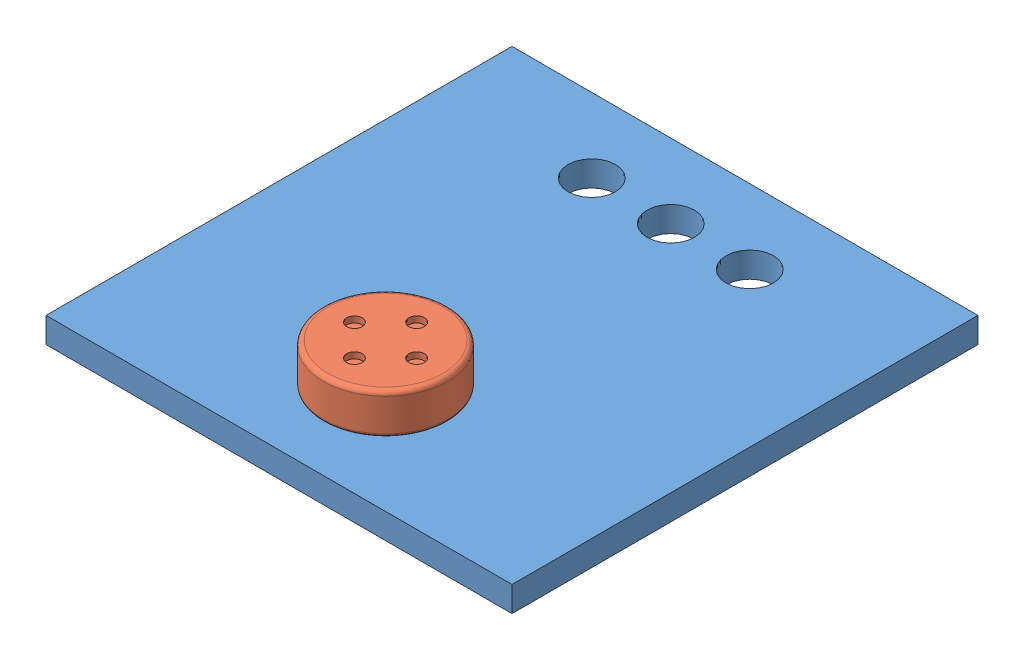
SolidWorks assembly Mic4013onBoard, configuration Default. Lengths in mm.
Overall size (14.99 2.16 14.99).
2 component instances, 2 part files, 2 mates.
Components (placement in the parent):
- mic_board-1: mic_board [Default] at (-0.7908 -0.2923 14.986) size (14.99 0.81 14.99)
- CUI_DEVICES_CMC-4013-SMT-TR-1: CUI_DEVICES_CMC-4013-SMT-TR [Default] at (-0.7857 0.5705 19.0583) x (0 1 0) z (0 0 1) size (1.35 4 4)
Mates (geometry in assembly coordinates):
- Coincident1: coincident anti-aligned: plane of mic_board-1 through (-0.7908 0.5205 14.986) normal (0 1 0); plane of CUI_DEVICES_CMC-4013-SMT-TR-1 through (-0.9989 0.5205 18.8447) normal (0 -1 0)
- Parallel1: parallel aligned: plane of mic_board-1 through (-0.7908 -0.2923 14.986) normal (0 -1 0); plane of CUI_DEVICES_CMC-4013-SMT-TR-1 through (-0.9989 0.5205 18.8447) normal (0 -1 0)
